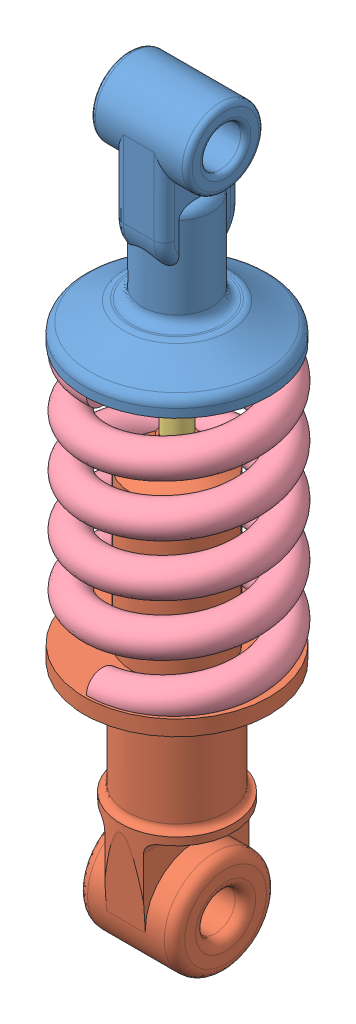
SolidWorks assembly Shock, configuration Default. Lengths in mm.
Overall size (46.33 186.03 47.49).
4 component instances, 4 part files, 12 mates.
Components (placement in the parent):
- Shock Anchor_11-1: Shock Anchor_11 [Default] at (152.5977 0 0) size (46 57.15 46)
- Shock Tube 1_11-1: Shock Tube 1_11 [Default] at (152.5977 -145.95 0) x (-1 0 0) z (0 0 1) size (46 109.21 46)
- Shock Absorber Rod_11-1: Shock Absorber Rod_11 [Default] at (152.5977 -66.839 0) x (0.425717 0 0.904857) z (-0.904857 0 0.425717) size (6.35 19.21 6.35)
- Shock Spring_11-1: Shock Spring_11 [Default] at (152.9274 -111.8466 -0.1604) size (46 72.22 47.49)
Mates (geometry in assembly coordinates):
- Concentric1: concentric: cylinder of Shock Anchor_11-1 through (158.9477 0 0) axis (-1 0 0) radius 5
- Coincident2: coincident aligned: plane of Shock Anchor_11-1 through (152.5977 0 0) normal (0 1 0)
- Coincident3: coincident aligned: plane of Shock Anchor_11-1 through (152.5977 0 0) normal (0 0 1)
- Concentric2: concentric aligned: circle of Shock Anchor_11-1; circle of Shock Absorber Rod_11-1
- Coincident4: coincident anti-aligned: plane of Shock Anchor_11-1 through (152.5977 -47.625 0) normal (0 -1 0); plane of Shock Absorber Rod_11-1 through (152.5977 -47.625 0) normal (0 1 0)
- Concentric3: concentric anti-aligned: cylinder of Shock Tube 1_11-1 through (152.5977 -92.6874 0) axis (0 1 0) radius 3.175; cylinder of Shock Absorber Rod_11-1 through (152.5977 -47.625 0) axis (0 -1 0) radius 3.175
- Coincident5: coincident anti-aligned: plane of Shock Anchor_11-1 through (152.5977 -47.625 0) normal (0 -1 0); plane of Shock Spring_11-1 through (152.9274 -47.625 -0.1604) normal (0 1 0)
- Lock1: lock: unknown of Shock Anchor_11-1; unknown of Shock Spring_11-1
- Parallel1: parallel anti-aligned: cylinder of Shock Anchor_11-1 through (158.9477 0 0) axis (-1 0 0) radius 5; cylinder of Shock Tube 1_11-1 through (140.5327 -165 0) axis (1 0 0) radius 4.9166
- Parallel4: parallel anti-aligned: line of Shock Anchor_11-1 through (0 24.13 164.6627) axis (0 0 -1); line of Shock Tube 1_11-1 through (24.13 140.5327 -165) axis (0 1 0)
- LimitDistance1: limit distance = 165 mm: line of Shock Tube 1_11-1 through (24.13 140.5327 -165) axis (0 1 0); line of Shock Anchor_11-1 through (0 24.13 164.6627) axis (0 0 -1)
- Distance1: distance = 165 mm: line of Shock Anchor_11-1 through (0 24.13 164.6627) axis (0 0 -1); line of Shock Tube 1_11-1 through (24.13 140.5327 -165) axis (0 1 0)
